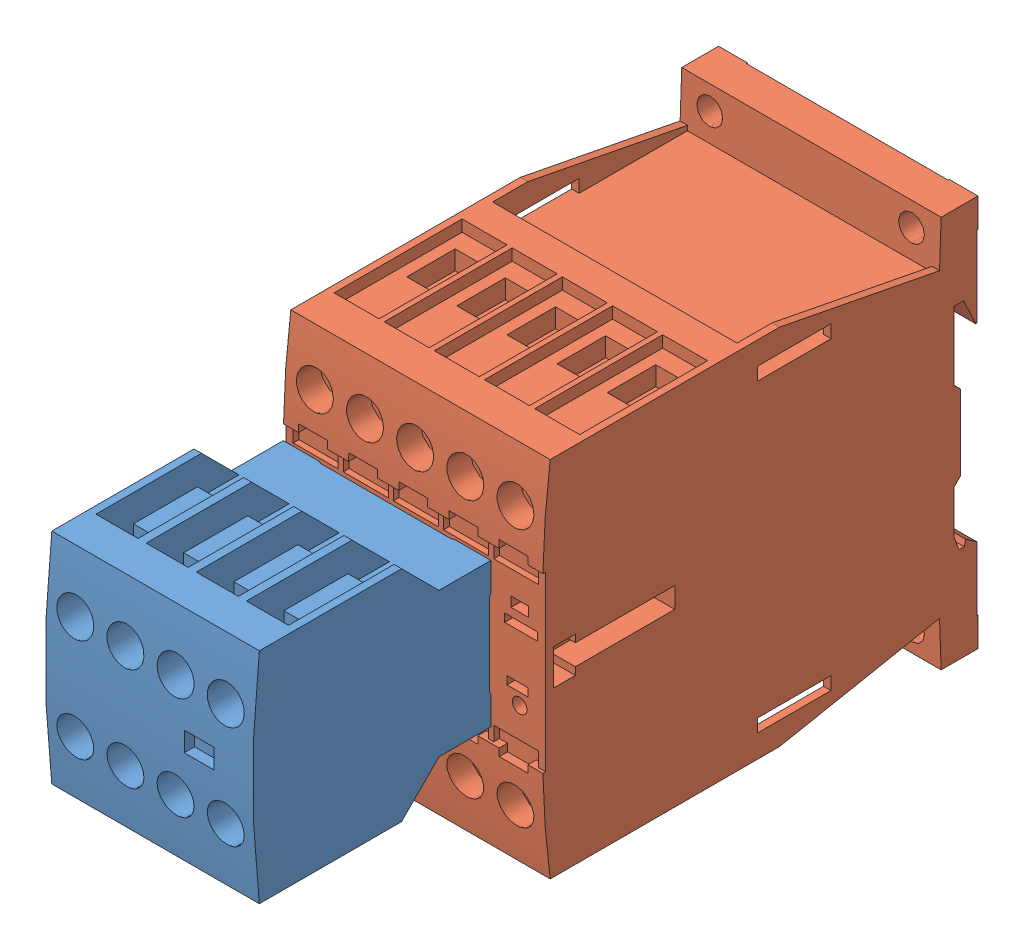
SolidWorks assembly SHRPRO-V1 18 EATON DILM contactor,4kW 230Vac 1break contact, configuration Predeterminado. Lengths in mm.
Overall size (45.5 68 116.3).
2 component instances, 2 part files, 4 mates.
Components (placement in the parent):
- dilm32-xhi22-1: dilm32-xhi22 [Default] at (17.5 -0.5 72.2) size (36 38 44.9)
- dilm9-01_230v50hz240v60hz_-1: dilm9-01_230v50hz240v60hz_ [Default] at origin size (45 68 75.5)
Mates (geometry in assembly coordinates):
- Coordinate1: coordinate: point of dilm9-01_230v50hz240v60hz_-1; point of assembly
- Coincident1: coincident: plane of dilm32-xhi22-1 through (35.5 49.0739 72) normal (0 0 -1); plane of dilm9-01_230v50hz240v60hz_-1 through (0 -15 72) normal (0 0 1)
- Coincident2: coincident: plane of dilm32-xhi22-1 through (14 61.5739 72.2) normal (-1 0 0); plane of dilm9-01_230v50hz240v60hz_-1 through (14 10.4 72) normal (1 0 0)
- Coincident3: coincident: plane of dilm32-xhi22-1 through (21 8.5 72.2) normal (0 -1 0); plane of dilm9-01_230v50hz240v60hz_-1 through (14 8.5 72) normal (0 1 0)
